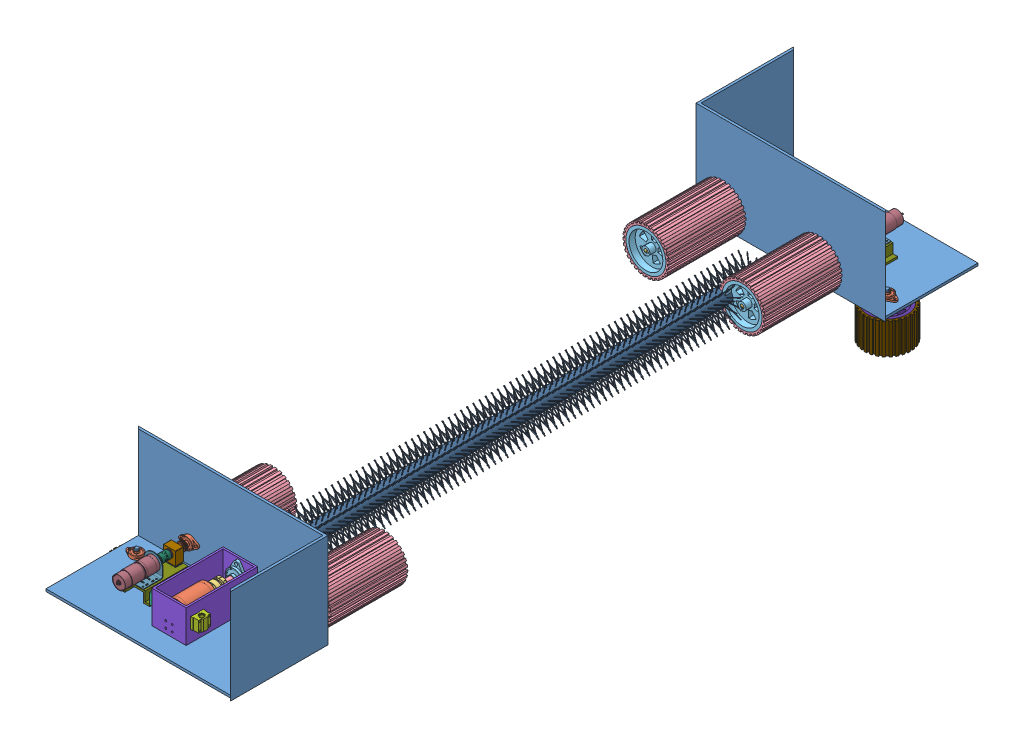
SolidWorks assembly moter in box assemly with 100mm supporting wheels - Copy2, configuration Default. Lengths in mm.
Overall size (727.54 420.46 2444.3).
186 component instances, 31 part files, 12 mates.
Components (placement in the parent):
- box-1: box [Default] at (214.7869 209.4239 556.9442) size (616 308 316)
- wheel without moter subassembley-1: wheel without moter subassembley [Default] at (384.8983 36.9 0) size (173.81 173.65 354)
  - KFL001 block flange ball bearing 12 diameter shaft-1: KFL001 block flange ball bearing 12 diameter shaft [Default] at (58.0648 247.4239 406.9442) x (-0.381567 0.924341 0) z (0.924341 0.381567 0) size (38 16 63)
  - wheel shaft-1: wheel shaft [Default] at (58.0648 247.4239 234.5442) x (0.174278 -0.984697 0) z (-0.984697 -0.174278 0) size (12 354 12)
  - wheel rubber-1: wheel rubber [Default] at (58.0648 247.4239 134.5442) x (-0.174278 0.984697 0) z (0.984697 0.174278 0) size (149.8 250 150)
  - wheel rim-1: wheel rim [Default] at (58.0648 247.4239 134.5442) x (-0.174278 0.984697 0) z (0.984697 0.174278 0) size (130 250 130)
  - Bearing House v1.step-1: Bearing House v1.step [Default] at (58.0648 227.9239 462.9398) x (-1 0 0) z (0 1 0) size (40 25 45.94)
    - SKF_61901-2Z.step-1: SKF_61901-2Z.step [Default] at (0 -8 19.5) x (0 -1 0) z (0 0 1) size (6 24 24)
      - SKF_61901-2Z_ball1.step-1: SKF_61901-2Z_ball1.step [Default] at (6 16.2812 -5.2901) x (-1 0 0) z (0 0 1) size (3.18 3.17 3.17)
      - SKF_61901-2Z_ball1.step-2: SKF_61901-2Z_ball1.step [Default] at (6 11.7812 -8.5595) x (-1 0 0) z (0 0 1) size (3.18 3.17 3.17)
      - SKF_61901-2Z_ball1.step-3: SKF_61901-2Z_ball1.step [Default] at (6 6.2188 -8.5595) x (-1 0 0) z (0 0 1) size (3.18 3.17 3.17)
      - SKF_61901-2Z_ball1.step-4: SKF_61901-2Z_ball1.step [Default] at (6 1.7188 -5.2901) x (-1 0 0) z (0 0 1) size (3.18 3.17 3.17)
      - SKF_61901-2Z_ball1.step-5: SKF_61901-2Z_ball1.step [Default] at (6 0 0) x (-1 0 0) z (0 0 1) size (3.18 3.17 3.17)
      - SKF_61901-2Z_ball1.step-6: SKF_61901-2Z_ball1.step [Default] at (6 1.7188 5.2901) x (-1 0 0) z (0 0 1) size (3.18 3.17 3.17)
      - SKF_61901-2Z_ball1.step-7: SKF_61901-2Z_ball1.step [Default] at (6 6.2188 8.5595) x (-1 0 0) z (0 0 1) size (3.18 3.17 3.17)
      - SKF_61901-2Z_ball1.step-8: SKF_61901-2Z_ball1.step [Default] at (6 11.7812 8.5595) x (-1 0 0) z (0 0 1) size (3.18 3.17 3.17)
      - SKF_61901-2Z_ball1.step-9: SKF_61901-2Z_ball1.step [Default] at (6 16.2812 5.2901) x (-1 0 0) z (0 0 1) size (3.18 3.17 3.17)
      - SKF_61901-2Z_ball1.step-10: SKF_61901-2Z_ball1.step [Default] at (6 18 0) x (-1 0 0) z (0 0 1) size (3.18 3.17 3.17)
      - SKF_61901-2Z_or.step-1: SKF_61901-2Z_or.step [Default] x (1 0 0) z (0 0 -1) size (6 24 24)
      - SKF_61901-2Z_ir.step-1: SKF_61901-2Z_ir.step [Default] x (1 0 0) z (0 0 -1) size (6 21.4 21.4)
    - SKF_61901-2Z.step-2: SKF_61901-2Z.step [Default] at (0 5 19.5) x (0 1 0) z (0 0 1) size (6 24 24)
      - SKF_61901-2Z_ball1.step-1: SKF_61901-2Z_ball1.step [Default] at (6 16.2812 -5.2901) x (-1 0 0) z (0 0 1) size (3.18 3.17 3.17)
      - SKF_61901-2Z_ball1.step-2: SKF_61901-2Z_ball1.step [Default] at (6 11.7812 -8.5595) x (-1 0 0) z (0 0 1) size (3.18 3.17 3.17)
      - SKF_61901-2Z_ball1.step-3: SKF_61901-2Z_ball1.step [Default] at (6 6.2188 -8.5595) x (-1 0 0) z (0 0 1) size (3.18 3.17 3.17)
      - SKF_61901-2Z_ball1.step-4: SKF_61901-2Z_ball1.step [Default] at (6 1.7188 -5.2901) x (-1 0 0) z (0 0 1) size (3.18 3.17 3.17)
      - SKF_61901-2Z_ball1.step-5: SKF_61901-2Z_ball1.step [Default] at (6 0 0) x (-1 0 0) z (0 0 1) size (3.18 3.17 3.17)
      - SKF_61901-2Z_ball1.step-6: SKF_61901-2Z_ball1.step [Default] at (6 1.7188 5.2901) x (-1 0 0) z (0 0 1) size (3.18 3.17 3.17)
      - SKF_61901-2Z_ball1.step-7: SKF_61901-2Z_ball1.step [Default] at (6 6.2188 8.5595) x (-1 0 0) z (0 0 1) size (3.18 3.17 3.17)
      - SKF_61901-2Z_ball1.step-8: SKF_61901-2Z_ball1.step [Default] at (6 11.7812 8.5595) x (-1 0 0) z (0 0 1) size (3.18 3.17 3.17)
      - SKF_61901-2Z_ball1.step-9: SKF_61901-2Z_ball1.step [Default] at (6 16.2812 5.2901) x (-1 0 0) z (0 0 1) size (3.18 3.17 3.17)
      - SKF_61901-2Z_ball1.step-10: SKF_61901-2Z_ball1.step [Default] at (6 18 0) x (-1 0 0) z (0 0 1) size (3.18 3.17 3.17)
      - SKF_61901-2Z_or.step-1: SKF_61901-2Z_or.step [Default] x (1 0 0) z (0 0 -1) size (6 24 24)
      - SKF_61901-2Z_ir.step-1: SKF_61901-2Z_ir.step [Default] x (1 0 0) z (0 0 -1) size (6 21.4 21.4)
    - Universal Bearing Housing.step-1: Universal Bearing Housing.step [Default] at (0 11.0044 14.0358) x (1 0 0) z (0 -1 0) size (40 43 25)
    - Universal Bearing Housing Spacer.step-1: Universal Bearing Housing Spacer.step [Default] at (0 -1.5 -7.4) x (1 0 0) z (0 1 0) size (40 3 25)
  - GT2 40T id 12mm bw 7mm-1: GT2 40T id 12mm bw 7mm [Výchozí] at (58.0648 247.4239 435.4442) x (0.924379 0.381477 0) z (0.381477 -0.924379 0) size (28.2 17 28.2)
  - height extender 25mm-1: height extender 25mm [Default] at (7.0648 186.5239 448.9398) size (102 37 25)
- Wheel with moter assembly-1: Wheel with moter assembly [Default] at (12.7256 37 0) size (163.26 163.44 510.81)
  - Motor DC PG45-1: Motor DC PG45 [Default] at (70.1664 247.4239 638.3442) x (0.707107 0.707107 0) z (-0.707107 0.707107 0) size (45 146.01 45)
  - Mounting Bracket Motor DC PG45 Orange-1: Mounting Bracket Motor DC PG45 Orange [Default] at (91.7552 243.9192 526.8442) x (-1 0 0) z (0 0 -1) size (60 60 63.93)
  - KFL001 block flange ball bearing 12 diameter shaft-1: KFL001 block flange ball bearing 12 diameter shaft [Default] at (70.1664 247.4239 406.9442) x (-0.034258 0.999413 0) z (0.999413 0.034258 0) size (38 16 63)
  - wheel shaft-1: wheel shaft [Default] at (70.1664 247.4239 234.5442) x (0.995554 -0.094191 0) z (-0.094191 -0.995554 0) size (12 354 12)
  - Shaft_Coupler_6.35x12mm-1: Shaft_Coupler_6.35x12mm [По умолчанию] at (70.1664 247.4239 508.9442) x (0.647293 0.762241 0) z (-0.762241 0.647293 0) size (25.41 30 25.41)
  - wheel rubber-1: wheel rubber [Default] at (70.1664 247.4239 134.5442) x (-0.995554 0.094191 0) z (0.094191 0.995554 0) size (149.8 250 150)
  - wheel rim-1: wheel rim [Default] at (70.1664 247.4239 134.5442) x (-0.995554 0.094191 0) z (0.094191 0.995554 0) size (130 250 130)
  - Bearing House v1.step-1: Bearing House v1.step [Default] at (70.1664 227.9239 462.9398) x (-1 0 0) z (0 1 0) size (40 25 45.94)
    - SKF_61901-2Z.step-1: SKF_61901-2Z.step [Default] at (0 -8 19.5) x (0 -1 0) z (0 0 1) size (6 24 24)
      - SKF_61901-2Z_ball1.step-1: SKF_61901-2Z_ball1.step [Default] at (6 16.2812 -5.2901) x (-1 0 0) z (0 0 1) size (3.18 3.17 3.17)
      - SKF_61901-2Z_ball1.step-2: SKF_61901-2Z_ball1.step [Default] at (6 11.7812 -8.5595) x (-1 0 0) z (0 0 1) size (3.18 3.17 3.17)
      - SKF_61901-2Z_ball1.step-3: SKF_61901-2Z_ball1.step [Default] at (6 6.2188 -8.5595) x (-1 0 0) z (0 0 1) size (3.18 3.17 3.17)
      - SKF_61901-2Z_ball1.step-4: SKF_61901-2Z_ball1.step [Default] at (6 1.7188 -5.2901) x (-1 0 0) z (0 0 1) size (3.18 3.17 3.17)
      - SKF_61901-2Z_ball1.step-5: SKF_61901-2Z_ball1.step [Default] at (6 0 0) x (-1 0 0) z (0 0 1) size (3.18 3.17 3.17)
      - SKF_61901-2Z_ball1.step-6: SKF_61901-2Z_ball1.step [Default] at (6 1.7188 5.2901) x (-1 0 0) z (0 0 1) size (3.18 3.17 3.17)
      - SKF_61901-2Z_ball1.step-7: SKF_61901-2Z_ball1.step [Default] at (6 6.2188 8.5595) x (-1 0 0) z (0 0 1) size (3.18 3.17 3.17)
      - SKF_61901-2Z_ball1.step-8: SKF_61901-2Z_ball1.step [Default] at (6 11.7812 8.5595) x (-1 0 0) z (0 0 1) size (3.18 3.17 3.17)
      - SKF_61901-2Z_ball1.step-9: SKF_61901-2Z_ball1.step [Default] at (6 16.2812 5.2901) x (-1 0 0) z (0 0 1) size (3.18 3.17 3.17)
      - SKF_61901-2Z_ball1.step-10: SKF_61901-2Z_ball1.step [Default] at (6 18 0) x (-1 0 0) z (0 0 1) size (3.18 3.17 3.17)
      - SKF_61901-2Z_or.step-1: SKF_61901-2Z_or.step [Default] x (1 0 0) z (0 0 -1) size (6 24 24)
      - SKF_61901-2Z_ir.step-1: SKF_61901-2Z_ir.step [Default] x (1 0 0) z (0 0 -1) size (6 21.4 21.4)
    - SKF_61901-2Z.step-2: SKF_61901-2Z.step [Default] at (0 5 19.5) x (0 1 0) z (0 0 1) size (6 24 24)
      - SKF_61901-2Z_ball1.step-1: SKF_61901-2Z_ball1.step [Default] at (6 16.2812 -5.2901) x (-1 0 0) z (0 0 1) size (3.18 3.17 3.17)
      - SKF_61901-2Z_ball1.step-2: SKF_61901-2Z_ball1.step [Default] at (6 11.7812 -8.5595) x (-1 0 0) z (0 0 1) size (3.18 3.17 3.17)
      - SKF_61901-2Z_ball1.step-3: SKF_61901-2Z_ball1.step [Default] at (6 6.2188 -8.5595) x (-1 0 0) z (0 0 1) size (3.18 3.17 3.17)
      - SKF_61901-2Z_ball1.step-4: SKF_61901-2Z_ball1.step [Default] at (6 1.7188 -5.2901) x (-1 0 0) z (0 0 1) size (3.18 3.17 3.17)
      - SKF_61901-2Z_ball1.step-5: SKF_61901-2Z_ball1.step [Default] at (6 0 0) x (-1 0 0) z (0 0 1) size (3.18 3.17 3.17)
      - SKF_61901-2Z_ball1.step-6: SKF_61901-2Z_ball1.step [Default] at (6 1.7188 5.2901) x (-1 0 0) z (0 0 1) size (3.18 3.17 3.17)
      - SKF_61901-2Z_ball1.step-7: SKF_61901-2Z_ball1.step [Default] at (6 6.2188 8.5595) x (-1 0 0) z (0 0 1) size (3.18 3.17 3.17)
      - SKF_61901-2Z_ball1.step-8: SKF_61901-2Z_ball1.step [Default] at (6 11.7812 8.5595) x (-1 0 0) z (0 0 1) size (3.18 3.17 3.17)
      - SKF_61901-2Z_ball1.step-9: SKF_61901-2Z_ball1.step [Default] at (6 16.2812 5.2901) x (-1 0 0) z (0 0 1) size (3.18 3.17 3.17)
      - SKF_61901-2Z_ball1.step-10: SKF_61901-2Z_ball1.step [Default] at (6 18 0) x (-1 0 0) z (0 0 1) size (3.18 3.17 3.17)
      - SKF_61901-2Z_or.step-1: SKF_61901-2Z_or.step [Default] x (1 0 0) z (0 0 -1) size (6 24 24)
      - SKF_61901-2Z_ir.step-1: SKF_61901-2Z_ir.step [Default] x (1 0 0) z (0 0 -1) size (6 21.4 21.4)
    - Universal Bearing Housing.step-1: Universal Bearing Housing.step [Default] at (0 11.0044 14.0358) x (1 0 0) z (0 -1 0) size (40 43 25)
    - Universal Bearing Housing Spacer.step-1: Universal Bearing Housing Spacer.step [Default] at (0 -1.5 -7.4) x (1 0 0) z (0 1 0) size (40 3 25)
  - GT2 40T id 12mm bw 7mm-1: GT2 40T id 12mm bw 7mm [Výchozí] at (70.1664 247.4239 435.4442) x (0.924379 0.381477 0) z (0.381477 -0.924379 0) size (28.2 17 28.2)
  - height extender 140mm-1: height extender 140mm [Default] at (19.1664 186.4239 448.9442) size (102 37 140)
- support wheel with block flange 100mm assembly-1: support wheel with block flange 100mm assembly [Default] at (-341.3848 337.3003 401.9413) x (0.243495 0 0.969902) z (0.969902 0 -0.243495) size (211.82 140 211.83)
  - side wheel (rubber+rim)-1: side wheel (rubber+rim) [Default] at (69.3134 97.8604 176.3592) size (211.82 100 211.83)
    - side wheel rim-1: side wheel rim [Default] at (68.1365 40.0161 108.3416) size (130 100 130)
    - side wheel rubber-1: side wheel rubber [Default] at (68.1365 40.0161 108.3416) x (0.734903 0 0.678172) z (-0.678172 0 0.734903) size (149.8 100 150)
  - support wheel shaft 100mm-1: support wheel shaft 100mm [Default] at (137.4499 201.8764 284.7008) x (1 0 0) z (0 0 -1) size (12 140 12)
  - KFL001 block flange ball bearing 12 diameter shaft-1: KFL001 block flange ball bearing 12 diameter shaft [Default] at (137.4499 119.8764 284.7008) x (-0.969898 0 0.243511) z (0.243511 0 0.969898) size (38 16 63)
- box_assemble v11-1: box_assemble v11 [Default] at (246.4099 223.4239 632.9442) x (-1 0 0) z (0 0 -1) size (171.55 172.21 2052.3)
  - box_assemble v11.step-1: box_assemble v11.step [Default] at origin size (168 106 256)
    - brush_motor_assembly.step-1: brush_motor_assembly.step [Default] at (0 -130 0) size (68.2 68.2 242)
      - my6812.step-1: my6812.step [Default] at (0 180 68.5) size (68.2 68.2 138.5)
      - SDCS-47C.step-1: SDCS-47C.step [Default] at (0 180 131.5) x (1 0 0) z (0 1 0) size (47 35.65 47)
      - axle_brush.step-1: axle_brush.step [Default] at (0 180 232) size (20 20 98)
    - KFL004 block flange ball bearing 20 diameter shaft.step-1: KFL004 block flange ball bearing 20 diameter shaft.step [Default] at (0 50 220) x (1 0 0) z (0 1 0) size (55 23 90)
    - Pillow Block Mk 1.step-1: Pillow Block Mk 1.step [Default] at (84 32.4199 211.75) x (0 0 -1) z (0 1 0) size (42 28 36)
    - Pillow Block Mk 1.step-2: Pillow Block Mk 1.step [Default] at (84 32.4199 50.25) x (0 0 -1) z (0 1 0) size (42 28 36)
    - Pillow Block Mk 1.step-3: Pillow Block Mk 1.step [Default] at origin size (42 28 36)
    - Pillow Block Mk 1 v1(Mirror).step-1: Pillow Block Mk 1 v1(Mirror).step [Default] at (-84 32.4199 211.75) x (0 0 -1) z (0 -1 0) size (42 28 36)
    - Pillow Block Mk 1 v1(Mirror).step-2: Pillow Block Mk 1 v1(Mirror).step [Default] at (-84 32.4199 50.25) x (0 0 -1) z (0 -1 0) size (42 28 36)
    - box_assemble.step-1: box_assemble.step [Default] at origin size (112 106 232)
    - box_assemble-0.step-1: box_assemble-0.step [Default] at origin size (10 10 20)
  - brush_coupling_assembly-1: brush_coupling_assembly [Default] at (1577.6534 -554.8547 2141.02) x (-0.167929 0.985799 0) z (-0.985799 -0.167929 0) size (149.39 1790 148.57)
    - Part2-1: Part2 [Default] at (861.1995 239.721 1453.6763) size (149.39 1560 148.57)
    - axle_brush v7-1: axle_brush v7 [Default] at (861.1995 204.722 1453.6763) x (-1 0 0) z (0 -1 0) size (25 28.24 110)
    - 5SM025025TK-StaffordManufacturingCorp.-3D-07-14-2023 (1).stp-1: 5SM025025TK-StaffordManufacturingCorp.-3D-07-14-2023 (1).stp [Default] at (861.1995 174.721 1453.6763) x (-1 0 0) z (0 0 -1) size (44.97 65 45)
    - 5SM025025TK-StaffordManufacturingCorp.-3D-07-14-2023 (1).stp-2: 5SM025025TK-StaffordManufacturingCorp.-3D-07-14-2023 (1).stp [Default] at (861.1995 1804.721 1453.6763) x (1 0 0) z (0 0 -1) size (44.97 65 45)
    - axle_brush v7-2: axle_brush v7 [Default] at (861.1995 1774.72 1453.6763) x (1 0 0) z (0 1 0) size (25 28.24 110)
  - SDCS-54C.step-1: SDCS-54C.step [Default] at (0 50 233) x (-0.975846 -0.21846 0) z (0.21846 -0.975846 0) size (54.01 42.32 54.01)
- moter in box assemly with 100mm supporting wheels - Copy (2)-1: moter in box assemly with 100mm supporting wheels - Copy (2) [Default] at (429.5737 2.4638 -1014.4116) x (-1 0 0) z (0 0 -1) size (671.77 418 580.4)
  - box-1: box [Default] at (214.7869 209.4239 556.9442) size (616 308 316)
  - wheel without moter subassembley-1: wheel without moter subassembley [Default] at (363.3222 36.9 0) size (173.81 173.65 354)
    - KFL001 block flange ball bearing 12 diameter shaft-1: KFL001 block flange ball bearing 12 diameter shaft [Default] at (58.0648 247.4239 406.9442) x (-0.381567 0.924341 0) z (0.924341 0.381567 0) size (38 16 63)
    - wheel shaft-1: wheel shaft [Default] at (58.0648 247.4239 234.5442) x (0.174278 -0.984697 0) z (-0.984697 -0.174278 0) size (12 354 12)
    - wheel rubber-1: wheel rubber [Default] at (58.0648 247.4239 134.5442) x (-0.174278 0.984697 0) z (0.984697 0.174278 0) size (149.8 250 150)
    - wheel rim-1: wheel rim [Default] at (58.0648 247.4239 134.5442) x (-0.174278 0.984697 0) z (0.984697 0.174278 0) size (130 250 130)
    - Bearing House v1.step-1: Bearing House v1.step [Default] at (58.0648 227.9239 462.9398) x (-1 0 0) z (0 1 0) size (40 25 45.94)
      - SKF_61901-2Z.step-1: SKF_61901-2Z.step [Default] at (0 -8 19.5) x (0 -1 0) z (0 0 1) size (6 24 24)
        - SKF_61901-2Z_ball1.step-1: SKF_61901-2Z_ball1.step [Default] at (6 16.2812 -5.2901) x (-1 0 0) z (0 0 1) size (3.18 3.17 3.17)
        - SKF_61901-2Z_ball1.step-2: SKF_61901-2Z_ball1.step [Default] at (6 11.7812 -8.5595) x (-1 0 0) z (0 0 1) size (3.18 3.17 3.17)
        - SKF_61901-2Z_ball1.step-3: SKF_61901-2Z_ball1.step [Default] at (6 6.2188 -8.5595) x (-1 0 0) z (0 0 1) size (3.18 3.17 3.17)
        - SKF_61901-2Z_ball1.step-4: SKF_61901-2Z_ball1.step [Default] at (6 1.7188 -5.2901) x (-1 0 0) z (0 0 1) size (3.18 3.17 3.17)
        - SKF_61901-2Z_ball1.step-5: SKF_61901-2Z_ball1.step [Default] at (6 0 0) x (-1 0 0) z (0 0 1) size (3.18 3.17 3.17)
        - SKF_61901-2Z_ball1.step-6: SKF_61901-2Z_ball1.step [Default] at (6 1.7188 5.2901) x (-1 0 0) z (0 0 1) size (3.18 3.17 3.17)
        - SKF_61901-2Z_ball1.step-7: SKF_61901-2Z_ball1.step [Default] at (6 6.2188 8.5595) x (-1 0 0) z (0 0 1) size (3.18 3.17 3.17)
        - SKF_61901-2Z_ball1.step-8: SKF_61901-2Z_ball1.step [Default] at (6 11.7812 8.5595) x (-1 0 0) z (0 0 1) size (3.18 3.17 3.17)
        - SKF_61901-2Z_ball1.step-9: SKF_61901-2Z_ball1.step [Default] at (6 16.2812 5.2901) x (-1 0 0) z (0 0 1) size (3.18 3.17 3.17)
        - SKF_61901-2Z_ball1.step-10: SKF_61901-2Z_ball1.step [Default] at (6 18 0) x (-1 0 0) z (0 0 1) size (3.18 3.17 3.17)
        - SKF_61901-2Z_or.step-1: SKF_61901-2Z_or.step [Default] x (1 0 0) z (0 0 -1) size (6 24 24)
        - SKF_61901-2Z_ir.step-1: SKF_61901-2Z_ir.step [Default] x (1 0 0) z (0 0 -1) size (6 21.4 21.4)
      - SKF_61901-2Z.step-2: SKF_61901-2Z.step [Default] at (0 5 19.5) x (0 1 0) z (0 0 1) size (6 24 24)
        - SKF_61901-2Z_ball1.step-1: SKF_61901-2Z_ball1.step [Default] at (6 16.2812 -5.2901) x (-1 0 0) z (0 0 1) size (3.18 3.17 3.17)
        - SKF_61901-2Z_ball1.step-2: SKF_61901-2Z_ball1.step [Default] at (6 11.7812 -8.5595) x (-1 0 0) z (0 0 1) size (3.18 3.17 3.17)
        - SKF_61901-2Z_ball1.step-3: SKF_61901-2Z_ball1.step [Default] at (6 6.2188 -8.5595) x (-1 0 0) z (0 0 1) size (3.18 3.17 3.17)
        - SKF_61901-2Z_ball1.step-4: SKF_61901-2Z_ball1.step [Default] at (6 1.7188 -5.2901) x (-1 0 0) z (0 0 1) size (3.18 3.17 3.17)
        - SKF_61901-2Z_ball1.step-5: SKF_61901-2Z_ball1.step [Default] at (6 0 0) x (-1 0 0) z (0 0 1) size (3.18 3.17 3.17)
        - SKF_61901-2Z_ball1.step-6: SKF_61901-2Z_ball1.step [Default] at (6 1.7188 5.2901) x (-1 0 0) z (0 0 1) size (3.18 3.17 3.17)
        - SKF_61901-2Z_ball1.step-7: SKF_61901-2Z_ball1.step [Default] at (6 6.2188 8.5595) x (-1 0 0) z (0 0 1) size (3.18 3.17 3.17)
        - SKF_61901-2Z_ball1.step-8: SKF_61901-2Z_ball1.step [Default] at (6 11.7812 8.5595) x (-1 0 0) z (0 0 1) size (3.18 3.17 3.17)
        - SKF_61901-2Z_ball1.step-9: SKF_61901-2Z_ball1.step [Default] at (6 16.2812 5.2901) x (-1 0 0) z (0 0 1) size (3.18 3.17 3.17)
        - SKF_61901-2Z_ball1.step-10: SKF_61901-2Z_ball1.step [Default] at (6 18 0) x (-1 0 0) z (0 0 1) size (3.18 3.17 3.17)
        - SKF_61901-2Z_or.step-1: SKF_61901-2Z_or.step [Default] x (1 0 0) z (0 0 -1) size (6 24 24)
        - SKF_61901-2Z_ir.step-1: SKF_61901-2Z_ir.step [Default] x (1 0 0) z (0 0 -1) size (6 21.4 21.4)
      - Universal Bearing Housing.step-1: Universal Bearing Housing.step [Default] at (0 11.0044 14.0358) x (1 0 0) z (0 -1 0) size (40 43 25)
      - Universal Bearing Housing Spacer.step-1: Universal Bearing Housing Spacer.step [Default] at (0 -1.5 -7.4) x (1 0 0) z (0 1 0) size (40 3 25)
    - GT2 40T id 12mm bw 7mm-1: GT2 40T id 12mm bw 7mm [Výchozí] at (58.0648 247.4239 435.4442) x (0.924379 0.381477 0) z (0.381477 -0.924379 0) size (28.2 17 28.2)
    - height extender 25mm-1: height extender 25mm [Default] at (7.0648 186.5239 448.9398) size (102 37 25)
  - Wheel with moter assembly-1: Wheel with moter assembly [Default] at (38.7886 37 0) size (163.26 163.44 510.81)
    - Motor DC PG45-1: Motor DC PG45 [Default] at (70.1664 247.4239 638.3442) x (0.707107 0.707107 0) z (-0.707107 0.707107 0) size (45 146.01 45)
    - Mounting Bracket Motor DC PG45 Orange-1: Mounting Bracket Motor DC PG45 Orange [Default] at (91.7552 243.9192 526.8442) x (-1 0 0) z (0 0 -1) size (60 60 63.93)
    - KFL001 block flange ball bearing 12 diameter shaft-1: KFL001 block flange ball bearing 12 diameter shaft [Default] at (70.1664 247.4239 406.9442) x (-0.034258 0.999413 0) z (0.999413 0.034258 0) size (38 16 63)
    - wheel shaft-1: wheel shaft [Default] at (70.1664 247.4239 234.5442) x (0.995554 -0.094191 0) z (-0.094191 -0.995554 0) size (12 354 12)
    - Shaft_Coupler_6.35x12mm-1: Shaft_Coupler_6.35x12mm [По умолчанию] at (70.1664 247.4239 508.9442) x (0.647293 0.762241 0) z (-0.762241 0.647293 0) size (25.41 30 25.41)
    - wheel rubber-1: wheel rubber [Default] at (70.1664 247.4239 134.5442) x (-0.995554 0.094191 0) z (0.094191 0.995554 0) size (149.8 250 150)
    - wheel rim-1: wheel rim [Default] at (70.1664 247.4239 134.5442) x (-0.995554 0.094191 0) z (0.094191 0.995554 0) size (130 250 130)
    - Bearing House v1.step-1: Bearing House v1.step [Default] at (70.1664 227.9239 462.9398) x (-1 0 0) z (0 1 0) size (40 25 45.94)
      - SKF_61901-2Z.step-1: SKF_61901-2Z.step [Default] at (0 -8 19.5) x (0 -1 0) z (0 0 1) size (6 24 24)
        - SKF_61901-2Z_ball1.step-1: SKF_61901-2Z_ball1.step [Default] at (6 16.2812 -5.2901) x (-1 0 0) z (0 0 1) size (3.18 3.17 3.17)
        - SKF_61901-2Z_ball1.step-2: SKF_61901-2Z_ball1.step [Default] at (6 11.7812 -8.5595) x (-1 0 0) z (0 0 1) size (3.18 3.17 3.17)
        - SKF_61901-2Z_ball1.step-3: SKF_61901-2Z_ball1.step [Default] at (6 6.2188 -8.5595) x (-1 0 0) z (0 0 1) size (3.18 3.17 3.17)
        - SKF_61901-2Z_ball1.step-4: SKF_61901-2Z_ball1.step [Default] at (6 1.7188 -5.2901) x (-1 0 0) z (0 0 1) size (3.18 3.17 3.17)
        - SKF_61901-2Z_ball1.step-5: SKF_61901-2Z_ball1.step [Default] at (6 0 0) x (-1 0 0) z (0 0 1) size (3.18 3.17 3.17)
        - SKF_61901-2Z_ball1.step-6: SKF_61901-2Z_ball1.step [Default] at (6 1.7188 5.2901) x (-1 0 0) z (0 0 1) size (3.18 3.17 3.17)
        - SKF_61901-2Z_ball1.step-7: SKF_61901-2Z_ball1.step [Default] at (6 6.2188 8.5595) x (-1 0 0) z (0 0 1) size (3.18 3.17 3.17)
        - SKF_61901-2Z_ball1.step-8: SKF_61901-2Z_ball1.step [Default] at (6 11.7812 8.5595) x (-1 0 0) z (0 0 1) size (3.18 3.17 3.17)
        - SKF_61901-2Z_ball1.step-9: SKF_61901-2Z_ball1.step [Default] at (6 16.2812 5.2901) x (-1 0 0) z (0 0 1) size (3.18 3.17 3.17)
        - SKF_61901-2Z_ball1.step-10: SKF_61901-2Z_ball1.step [Default] at (6 18 0) x (-1 0 0) z (0 0 1) size (3.18 3.17 3.17)
        - SKF_61901-2Z_or.step-1: SKF_61901-2Z_or.step [Default] x (1 0 0) z (0 0 -1) size (6 24 24)
        - SKF_61901-2Z_ir.step-1: SKF_61901-2Z_ir.step [Default] x (1 0 0) z (0 0 -1) size (6 21.4 21.4)
      - SKF_61901-2Z.step-2: SKF_61901-2Z.step [Default] at (0 5 19.5) x (0 1 0) z (0 0 1) size (6 24 24)
        - SKF_61901-2Z_ball1.step-1: SKF_61901-2Z_ball1.step [Default] at (6 16.2812 -5.2901) x (-1 0 0) z (0 0 1) size (3.18 3.17 3.17)
        - SKF_61901-2Z_ball1.step-2: SKF_61901-2Z_ball1.step [Default] at (6 11.7812 -8.5595) x (-1 0 0) z (0 0 1) size (3.18 3.17 3.17)
        - SKF_61901-2Z_ball1.step-3: SKF_61901-2Z_ball1.step [Default] at (6 6.2188 -8.5595) x (-1 0 0) z (0 0 1) size (3.18 3.17 3.17)
        - SKF_61901-2Z_ball1.step-4: SKF_61901-2Z_ball1.step [Default] at (6 1.7188 -5.2901) x (-1 0 0) z (0 0 1) size (3.18 3.17 3.17)
        - SKF_61901-2Z_ball1.step-5: SKF_61901-2Z_ball1.step [Default] at (6 0 0) x (-1 0 0) z (0 0 1) size (3.18 3.17 3.17)
        - SKF_61901-2Z_ball1.step-6: SKF_61901-2Z_ball1.step [Default] at (6 1.7188 5.2901) x (-1 0 0) z (0 0 1) size (3.18 3.17 3.17)
        - SKF_61901-2Z_ball1.step-7: SKF_61901-2Z_ball1.step [Default] at (6 6.2188 8.5595) x (-1 0 0) z (0 0 1) size (3.18 3.17 3.17)
        - SKF_61901-2Z_ball1.step-8: SKF_61901-2Z_ball1.step [Default] at (6 11.7812 8.5595) x (-1 0 0) z (0 0 1) size (3.18 3.17 3.17)
        - SKF_61901-2Z_ball1.step-9: SKF_61901-2Z_ball1.step [Default] at (6 16.2812 5.2901) x (-1 0 0) z (0 0 1) size (3.18 3.17 3.17)
        - SKF_61901-2Z_ball1.step-10: SKF_61901-2Z_ball1.step [Default] at (6 18 0) x (-1 0 0) z (0 0 1) size (3.18 3.17 3.17)
        - SKF_61901-2Z_or.step-1: SKF_61901-2Z_or.step [Default] x (1 0 0) z (0 0 -1) size (6 24 24)
        - SKF_61901-2Z_ir.step-1: SKF_61901-2Z_ir.step [Default] x (1 0 0) z (0 0 -1) size (6 21.4 21.4)
      - Universal Bearing Housing.step-1: Universal Bearing Housing.step [Default] at (0 11.0044 14.0358) x (1 0 0) z (0 -1 0) size (40 43 25)
      - Universal Bearing Housing Spacer.step-1: Universal Bearing Housing Spacer.step [Default] at (0 -1.5 -7.4) x (1 0 0) z (0 1 0) size (40 3 25)
    - GT2 40T id 12mm bw 7mm-1: GT2 40T id 12mm bw 7mm [Výchozí] at (70.1664 247.4239 435.4442) x (0.924379 0.381477 0) z (0.381477 -0.924379 0) size (28.2 17 28.2)
    - height extender 140mm-1: height extender 140mm [Default] at (19.1664 186.4239 448.9442) size (102 37 140)
  - support wheel with block flange 100mm assembly-1: support wheel with block flange 100mm assembly [Default] at (-341.3848 337.3003 401.9413) x (0.243495 0 0.969902) z (0.969902 0 -0.243495) size (211.82 140 211.83)
    - side wheel (rubber+rim)-1: side wheel (rubber+rim) [Default] at (69.3134 97.8604 176.3592) size (211.82 100 211.83)
      - side wheel rim-1: side wheel rim [Default] at (68.1365 40.0161 108.3416) size (130 100 130)
      - side wheel rubber-1: side wheel rubber [Default] at (68.1365 40.0161 108.3416) x (0.734903 0 0.678172) z (-0.678172 0 0.734903) size (149.8 100 150)
    - support wheel shaft 100mm-1: support wheel shaft 100mm [Default] at (137.4499 201.8764 284.7008) x (1 0 0) z (0 0 -1) size (12 140 12)
    - KFL001 block flange ball bearing 12 diameter shaft-1: KFL001 block flange ball bearing 12 diameter shaft [Default] at (137.4499 119.8764 284.7008) x (-0.969898 0 0.243511) z (0.243511 0 0.969898) size (38 16 63)
Mates (geometry in assembly coordinates):
- Parallel6: parallel anti-aligned: line of box-1 through (-85.2131 217.4239 406.9442) axis (0 0 1); line of wheel without moter subassembley-1/Bearing House v1.step-1/Universal Bearing Housing Spacer.step-1 through (422.9631 254.4239 472.9398) axis (0 0 -1)
- Parallel7: parallel anti-aligned: line of box-1 through (-85.2131 217.4239 706.9442) axis (1 0 0); line of wheel without moter subassembley-1/Bearing House v1.step-1/Universal Bearing Housing Spacer.step-1 through (461.9631 254.4239 473.9398) axis (-1 0 0)
- Coincident18: coincident anti-aligned: plane of box-1 through (214.7869 517.4239 406.9442) normal (0 0 1); plane of wheel without moter subassembley-1/KFL001 block flange ball bearing 12 diameter shaft-1 through (442.9631 284.3239 406.9442) normal (0 0 -1)
- Coincident22: coincident anti-aligned: plane of box-1 through (214.7869 217.4239 556.9442) normal (0 1 0); plane of wheel without moter subassembley-1/height extender 25mm-1 through (412.9631 217.4239 473.9398) normal (0 -1 0)
- Coincident23: coincident anti-aligned: plane of box-1 through (214.7869 217.4239 556.9442) normal (0 1 0); plane of Wheel with moter assembly-1/height extender 140mm-1 through (52.892 217.4239 588.9442) normal (0 -1 0)
- Coincident24: coincident anti-aligned: plane of box-1 through (214.7869 517.4239 406.9442) normal (0 0 1); plane of Wheel with moter assembly-1/KFL001 block flange ball bearing 12 diameter shaft-1 through (82.892 284.4239 406.9442) normal (0 0 -1)
- Coincident25: coincident anti-aligned: plane of box-1 through (214.7869 217.4239 556.9442) normal (0 1 0); plane of support wheel with block flange 100mm assembly-1/KFL001 block flange ball bearing 12 diameter shaft-1 through (-31.7846 217.4239 465.9312) normal (0 -1 0)
- Angle3: planar angle = 0.499688 rad aligned: line of support wheel with block flange 100mm assembly-1/KFL001 block flange ball bearing 12 diameter shaft-1 through (-22.6807 217.4239 482.6081) axis (0.877732 0 -0.479152); line of box-1 through (-85.2131 217.4239 406.9442) axis (1 0 0)
- Coincident26: coincident anti-aligned: plane of box-1 through (214.7869 217.4239 556.9442) normal (0 1 0); plane of box_assemble v11-1/box_assemble v11.step-1/box_assemble.step-1 through (246.4099 217.4239 522.9442) normal (0 -1 0)
- Coincident27: coincident anti-aligned: plane of box-1 through (214.7869 517.4239 406.9442) normal (0 0 1); plane of box_assemble v11-1/box_assemble v11.step-1/box_assemble.step-1 through (296.4099 223.4239 406.9442) normal (0 0 -1)
- Distance2: distance = 1812.3 mm anti-aligned: plane of box-1 through (214.7869 517.4239 398.9442) normal (0 0 -1); plane of moter in box assemly with 100mm supporting wheels - Copy (2)-1/box-1 through (214.7869 519.8877 -1413.3558) normal (0 0 1)
- Distance4: distance = 600 mm anti-aligned: plane of box-1 through (514.7869 517.4239 556.9442) normal (-1 0 0); plane of moter in box assemly with 100mm supporting wheels - Copy (2)-1/box-1 through (-85.2131 519.8877 -1571.3558) normal (1 0 0)
